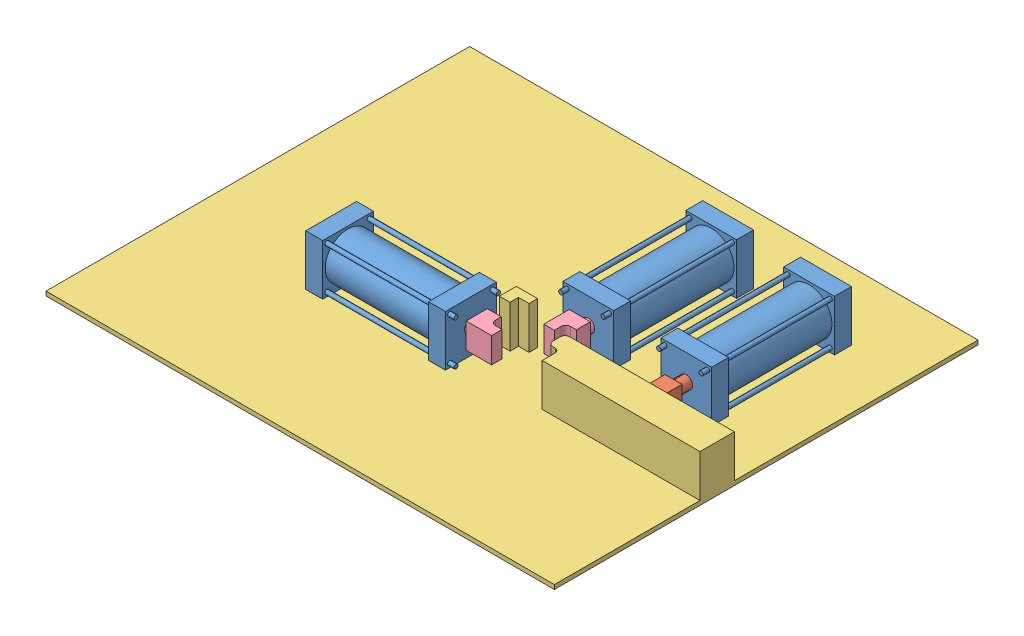
SolidWorks assembly Solidworks 3D model - Assembly, configuration Default. Lengths in mm.
Overall size (1200 130 1000).
7 component instances, 4 part files, 6 mates.
Components (placement in the parent):
- Base-1: Base [Default] at (700.0194 60 -21.4718) x (1 0 0) z (0 -1 0) size (120 345 120)
- Piston-1: Piston [Default] at (700.0194 60 -6.4718) x (1 0 0) z (0 -1 0) size (100 345 100)
- WorkGround-1: WorkGround [Default] at (298.7807 -10 278.5282) size (1200 110 1000)
- Base-2: Base [Default] at (468.9528 60 -21.4718) x (1 0 0) z (0 -1 0) size (120 345 120)
- Base-3: Base [Default] at (41.9659 60 408.7013) x (0 0 -1) z (0 -1 0) size (120 345 120)
- Piston1-1: Piston1 [Default] at (90.6262 60 408.7013) x (0 0 1) z (0 1 0) size (100 315 100)
- Piston1-2: Piston1 [Default] at (468.9528 60 33.7267) x (-1 0 0) z (0 1 0) size (100 315 100)
Mates (geometry in assembly coordinates):
- Concentric1: concentric aligned: cylinder of Base-1 through (700.0194 60 228.5282) axis (0 0 -1) radius 54; cylinder of Piston-1 through (700.0194 60 298.5282) axis (0 0 -1) radius 15
- Concentric4: concentric aligned: cylinder of Base-3 through (291.9659 60 408.7013) axis (-1 0 0) radius 54; cylinder of Piston1-1 through (345.6262 60 408.7013) axis (-1 0 0) radius 15
- Concentric5: concentric aligned: cylinder of Base-2 through (468.9528 60 228.5282) axis (0 0 -1) radius 54; cylinder of Piston1-2 through (468.9528 60 288.7267) axis (0 0 -1) radius 15
- Coincident26: coincident anti-aligned: plane of WorkGround-1 through (298.7807 0 278.5282) normal (0 1 0); plane of Base-3 through (331.9659 0 468.7013) normal (0 -1 0)
- Coincident27: coincident anti-aligned: plane of WorkGround-1 through (298.7807 0 278.5282) normal (0 1 0); plane of Base-2 through (408.9528 0 268.5282) normal (0 -1 0)
- Coincident28: coincident anti-aligned: plane of Base-1 through (640.0194 0 268.5282) normal (0 -1 0); plane of WorkGround-1 through (298.7807 0 278.5282) normal (0 1 0)
